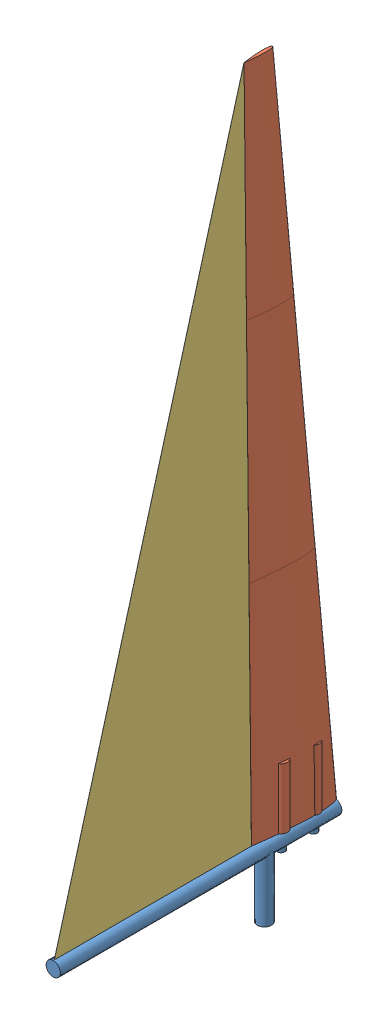
SolidWorks assembly Sail Assembly, configuration Default. Lengths in mm.
Overall size (12.7 669.38 250.95).
3 component instances, 3 part files, 6 mates.
Components (placement in the parent):
- Sail Mast-1: Sail Mast [Default] at (100.3536 106.544 204.4346) size (12.7 114.3 250)
- Sail Airfoil-1: Sail Airfoil [Default] at (100.3536 170.044 140.9846) x (0 0 1) z (-1 0 0) size (81.55 605.88 11.14)
- Sail Sheet-1: Sail Sheet [Default] at (100.3216 170.044 390.9846) size (0.06 605.88 175)
Mates (geometry in assembly coordinates):
- Concentric1: concentric aligned: cylinder of Sail Mast-1 through (100.3536 220.844 160.9846) axis (0 -1 0) radius 3.5; cylinder of Sail Airfoil-1 through (100.3536 220.844 160.9846) axis (0 -1 0) radius 5.5
- Concentric2: concentric aligned: cylinder of Sail Mast-1 through (100.3536 220.844 189.5596) axis (0 -1 0) radius 3.5; cylinder of Sail Airfoil-1 through (100.3536 220.844 189.5596) axis (0 -1 0) radius 5.5
- Coincident1: coincident anti-aligned: plane of Sail Mast-1 through (100.3536 220.844 160.9846) normal (0 1 0); plane of Sail Airfoil-1 through (100.3536 220.844 160.9846) normal (0 -1 0)
- Coincident2: coincident anti-aligned: plane of Sail Airfoil-1 through (100.3536 169.2333 215.9759) normal (0 -0.01081 0.999942); plane of Sail Sheet-1 through (100.3856 775.924 222.5346) normal (0 0.01081 -0.999942)
- Coincident3: coincident: plane of Sail Airfoil-1 through (100.3536 775.924 197.1346) normal (0 1 0); line of Sail Sheet-1 through (100.3856 775.924 222.5346) axis (-1 0 0)
- Coincident5: coincident: line of Sail Airfoil-1 through (100.4272 373.244 218.1814) axis (0.000103 -0.999942 -0.01081); point of Sail Sheet-1
